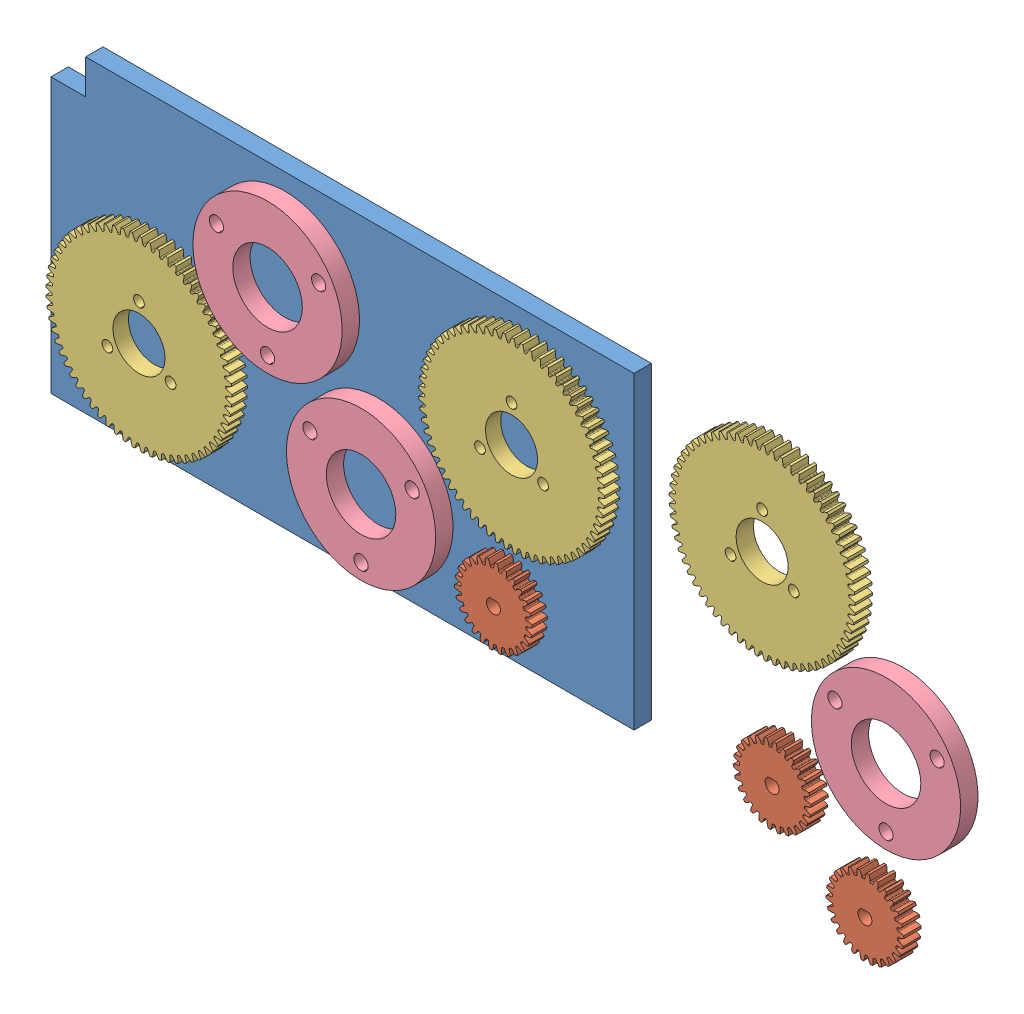
SolidWorks assembly 切り出し用, configuration V3. Lengths in mm.
Overall size (264.73 117.12 11.37).
10 component instances, 4 part files, 9 mates.
Components (placement in the parent):
- 板1-1: 板1 [板2] at (105.8642 175.0182 246.9028) size (168 89 5)
- エンコーダ歯車-1: エンコーダ歯車 [デフォルト] at (233.6714 139.499 253.441) size (22.4 22.38 5)
- モータ伝達歯車-1: モータ伝達歯車 [アクリル切り出し] at (231.7672 197.4158 251.9028) size (53.59 53.59 5)
- モータ伝達歯車-2: モータ伝達歯車 [アクリル切り出し] at (51.6763 159.0615 251.352) size (53.59 53.59 5)
- モータ伝達歯車-4: モータ伝達歯車 [アクリル切り出し] at (158.9646 187.3775 251.3011) size (53.59 53.59 5)
- エンコーダ歯車-4: エンコーダ歯車 [デフォルト] at (153.7068 144.4516 253.7584) size (22.4 22.38 5)
- エンコーダ歯車-5: エンコーダ歯車 [デフォルト] at (258.6136 118.2846 251.6222) size (22.4 22.38 5)
- モータ取り付けアクリル板-1: モータ取り付けアクリル板 [ﾃﾞﾌｫﾙﾄ] at (116.5406 154.2845 249.7381) size (43 43 5)
- モータ取り付けアクリル板-2: モータ取り付けアクリル板 [ﾃﾞﾌｫﾙﾄ] at (90.6318 193.5035 250.7696) size (43 43 5)
- モータ取り付けアクリル板-3: モータ取り付けアクリル板 [ﾃﾞﾌｫﾙﾄ] at (265.0985 160.0132 247.0382) size (43 43 5)
Mates (geometry in assembly coordinates):
- 一致1: coincident: plane of 板1-1 through (105.8642 175.0182 249.4028) normal (0 0 1); plane of エンコーダ歯車-1 through (247.9185 158.1036 249.4028) normal (0 0 -1)
- 一致2: coincident: plane of 板1-1 through (105.8642 175.0182 249.4028) normal (0 0 1); plane of モータ伝達歯車-1 through (231.7672 197.4158 249.4028) normal (0 0 -1)
- 一致3: coincident: plane of 板1-1 through (105.8642 175.0182 249.4028) normal (0 0 1); plane of モータ伝達歯車-2 through (123.1622 199.2807 249.4028) normal (0 0 -1)
- 一致4: coincident: plane of 板1-1 through (105.8642 175.0182 249.4028) normal (0 0 1); plane of モータ伝達歯車-4 through (180.1568 150.4978 249.4028) normal (0 0 -1)
- 一致5: coincident: plane of 板1-1 through (105.8642 175.0182 249.4028) normal (0 0 1); plane of エンコーダ歯車-4 through (240.0209 133.8246 249.4028) normal (0 0 -1)
- 一致6: coincident: plane of 板1-1 through (105.8642 175.0182 249.4028) normal (0 0 1); plane of エンコーダ歯車-5 through (221.686 155.233 249.4028) normal (0 0 -1)
- 一致7: coincident: plane of 板1-1 through (105.8642 175.0182 249.4028) normal (0 0 1); plane of モータ取り付けアクリル板-1 through (127.892 146.9725 249.4028) normal (0 0 -1)
- 一致8: coincident: plane of 板1-1 through (105.8642 175.0182 249.4028) normal (0 0 1); plane of モータ取り付けアクリル板-2 through (81.1717 146.6186 249.4028) normal (0 0 -1)
- 一致9: coincident: plane of 板1-1 through (105.8642 175.0182 249.4028) normal (0 0 1); plane of モータ取り付けアクリル板-3 through (177.7773 202.0988 249.4028) normal (0 0 -1)
